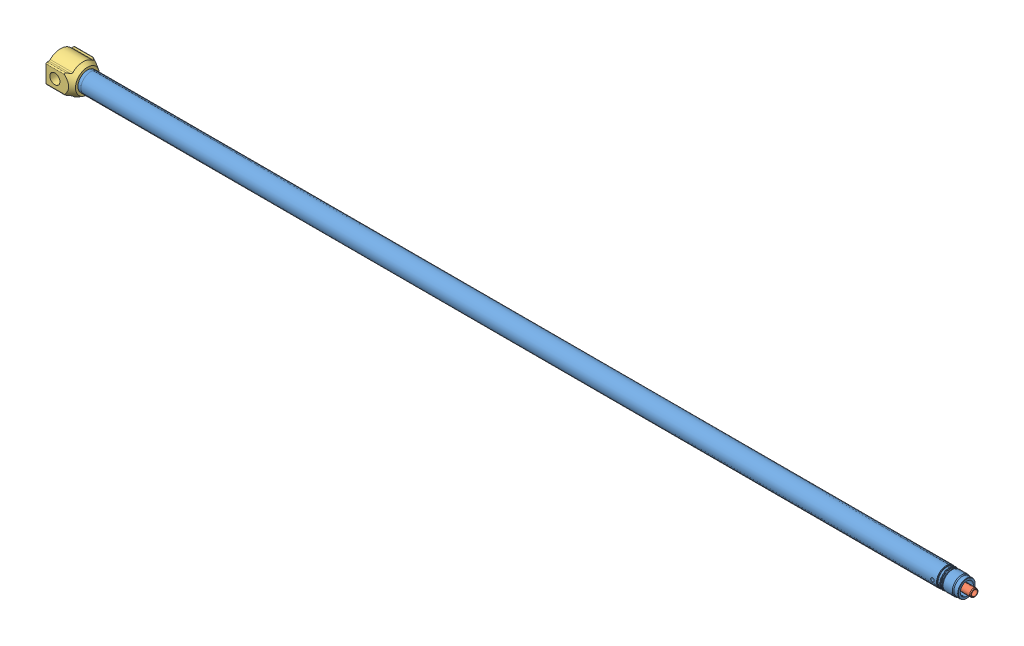
SolidWorks assembly 6344581, configuration Default. Lengths in mm.
Overall size (2369 75 75).
3 component instances, 3 part files, 9 mates.
Components (placement in the parent):
- 6344582-1: 6344582 [Default] at (42 0 0) size (2284 50 50)
- 6344583-1: 6344583 [Default] at (34 0 0) size (2312 20 20)
- 6304259-1: 6304259 [Default] at origin size (70 75 75)
Mates (geometry in assembly coordinates):
- Coincident3: coincident aligned: plane of 6344583-1 through (34 0 0) normal (0 1 0); plane of assembly through (0 0 0) normal (0 1 0)
- Coincident5: coincident aligned: plane of 6344582-1 through (42 0 0) normal (0 1 0); plane of assembly through (0 0 0) normal (0 1 0)
- Concentric4: concentric aligned: cylinder of 6344582-1 through (42 0 0) axis (-1 0 0) radius 25; cylinder of 6304259-1 through (-65.5921 0 0) axis (-1 0 0) radius 37.5
- Coincident6: coincident anti-aligned: plane of 6344582-1 through (47 24 0) normal (-1 0 0); plane of 6304259-1 through (47 31 0) normal (1 0 0)
- Parallel1: parallel aligned: plane of 6344582-1 through (42 0 0) normal (0 1 0); plane of assembly through (0 0 0) normal (0 1 0)
- Coincident7: coincident: point of 6304259-1
- Parallel2: parallel aligned: plane of 6304259-1 through (0 0 0) normal (0 0 1); plane of assembly through (0 0 0) normal (0 0 1)
- Coincident8: coincident anti-aligned: plane of 6344583-1 through (34 10 0) normal (-1 0 0); plane of 6304259-1 through (34 10 0) normal (1 0 0)
- Concentric5: concentric aligned: cylinder of 6344583-1 through (34 0 0) axis (-1 0 0) radius 10; cylinder of 6304259-1 through (-65.5921 0 0) axis (-1 0 0) radius 37.5
